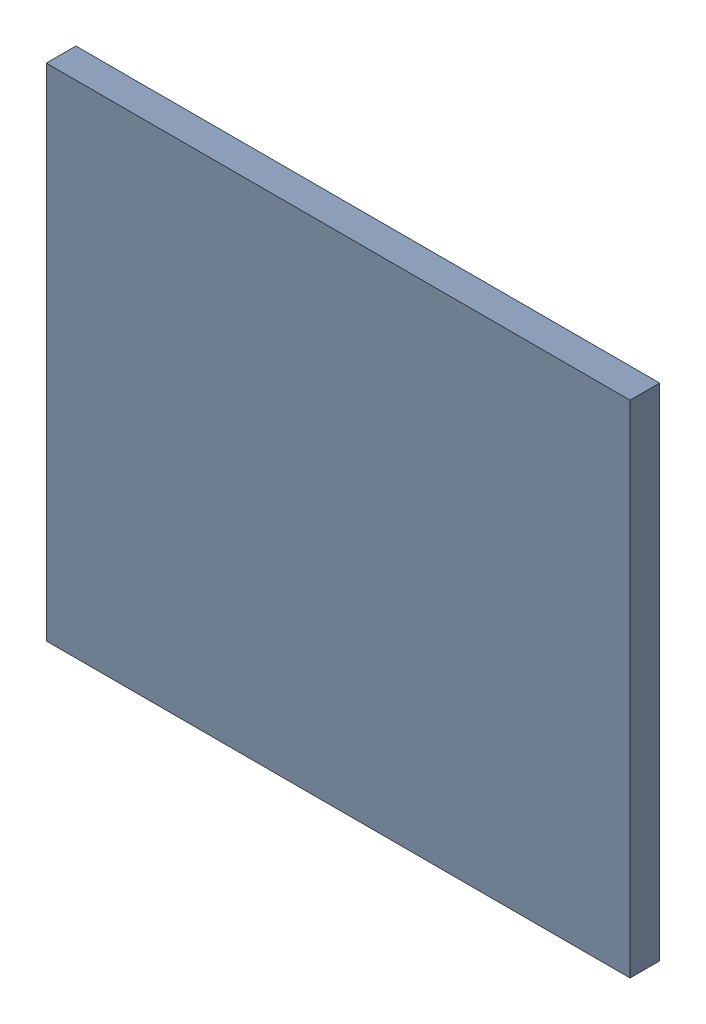
SolidWorks assembly Pad R1-1(26.95mm,40mm) on Top Layer, configuration Predeterminado. Lengths in mm.
Overall size (0.7 0.6 0.04).
2 component instances, 1 part files, 0 mates.
Components (placement in the parent):
- Pad R1-1(26.95mm,40mm) on Top Layer-1-1: Pad R1-1(26.95mm,40mm) on Top Layer-1 [Predeterminado] at (-68.317 -44.187 -0.0457) size (0.7 0.6 0.04)
  - Pad R1-1(26.95mm,40mm) on Top Layer-Part-1-1: Pad R1-1(26.95mm,40mm) on Top Layer-Part-1 [Predeterminado] at origin size (0.7 0.6 0.04)
